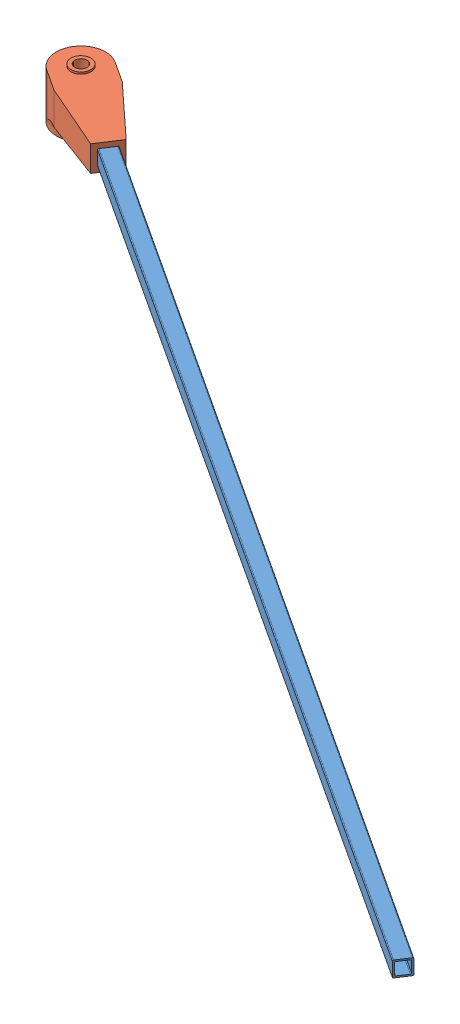
SolidWorks assembly Forarm_ASM, configuration Default. Lengths in mm.
Overall size (490.72 25.4 328.81).
2 component instances, 2 part files, 6 mates.
Components (placement in the parent):
- Forearm-1: Forearm [Default] at (240.5878 20.72 200.3247) x (0.546944 0 -0.837169) z (-0.837169 0 -0.546944) size (7.9 7.9 550)
- Elbow2V2-1: Elbow2V2 [Default] at (-0.0983 43.42 43.0782) x (0.837169 0 0.546944) z (0.546944 0 -0.837169) size (60.44 25.4 26.3)
Mates (geometry in assembly coordinates):
- Coincident1: coincident anti-aligned: plane of Elbow1-1 through (30.8608 15.3381 32.0055) normal (0 0 1); plane of Forearm-1 through (12.5268 16.77 46.6082) normal (0.546944 0 -0.837169)
- Coincident2: coincident anti-aligned: plane of Elbow1-1 through (30.8608 19.3381 36.0055) normal (1 0 0); plane of Forearm-1 through (10.3663 20.72 49.915) normal (-0.837169 0 -0.546944)
- Coincident4: coincident: line of Elbow1-1 through (50.8608 23.3381 32.0055) axis (0 0 1); plane of Forearm-1 through (8.2059 24.67 53.2218) normal (0 1 0)
- Coincident5: coincident anti-aligned: plane of Forearm-1 through (8.2059 24.67 53.2218) normal (0 1 0); plane of Elbow2V2-1 through (12.5268 24.67 46.6082) normal (0 -1 0)
- Coincident6: coincident anti-aligned: plane of Forearm-1 through (12.5268 16.77 46.6082) normal (0.546944 0 -0.837169); plane of Elbow2V2-1 through (12.5268 16.77 46.6082) normal (-0.546944 0 0.837169)
- Coincident7: coincident: line of Forearm-1 through (12.5268 24.17 46.6082) axis (0 -1 0); plane of Elbow2V2-1 through (10.3663 43.42 49.915) normal (0.837169 0 0.546944)
